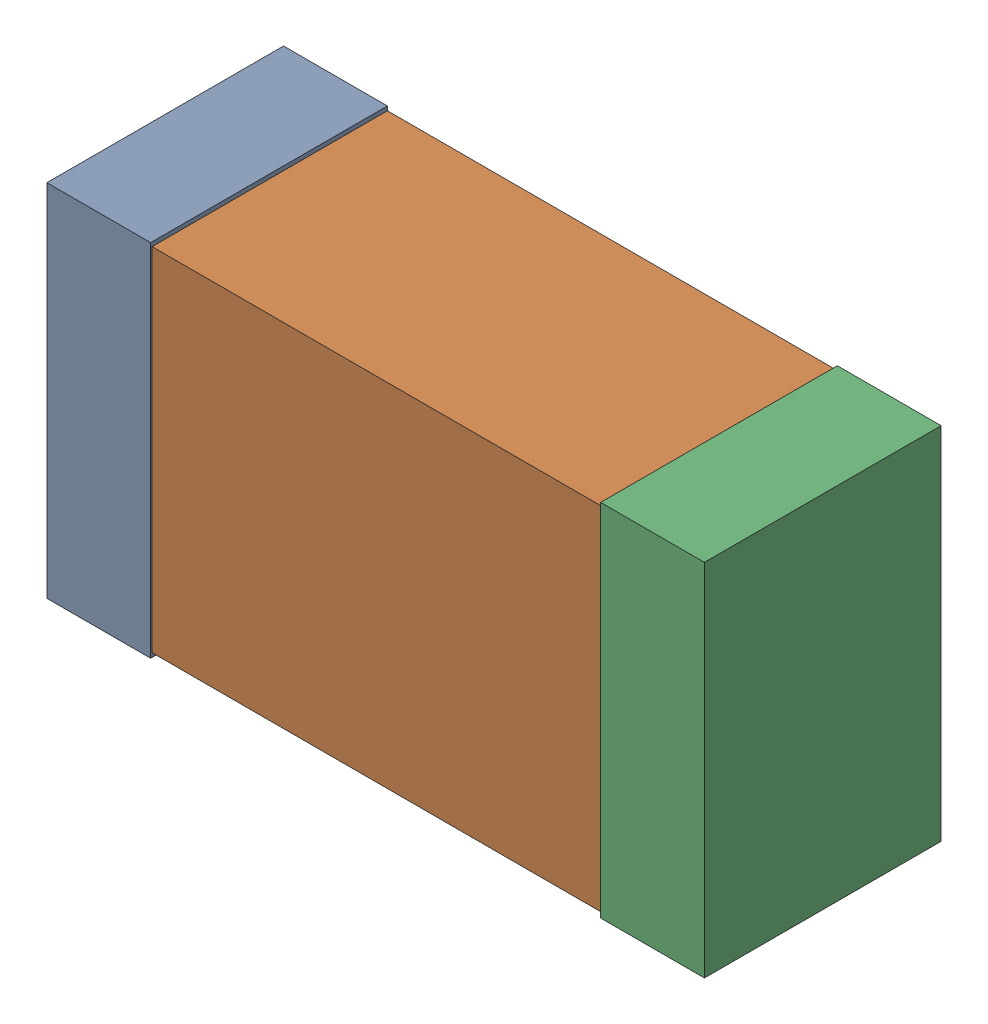
SolidWorks assembly C13_Motor_6Kanaloa_v2.0.0_Motor, configuration Default. Lengths in mm.
Overall size (2.38 1.3 0.85).
6 component instances, 2 part files, 0 mates.
Components (placement in the parent):
- 352877648-1: 352877648 [Default] at (59.648 142.24 0) size (0.38 1.3 0.85)
  - Extruded_14-1: Extruded_14 [Default] at origin size (0.38 1.3 0.85)
- 352877392-1: 352877392 [Default] at (60.648 142.24 0) size (2.2 1.27 0.85)
  - Extruded_15-1: Extruded_15 [Default] at origin size (2.2 1.27 0.85)
- 352877648-2: 352877648 [Default] at (61.648 142.24 0) size (0.38 1.3 0.85)
  - Extruded_14-1: Extruded_14 [Default] at origin size (0.38 1.3 0.85)
